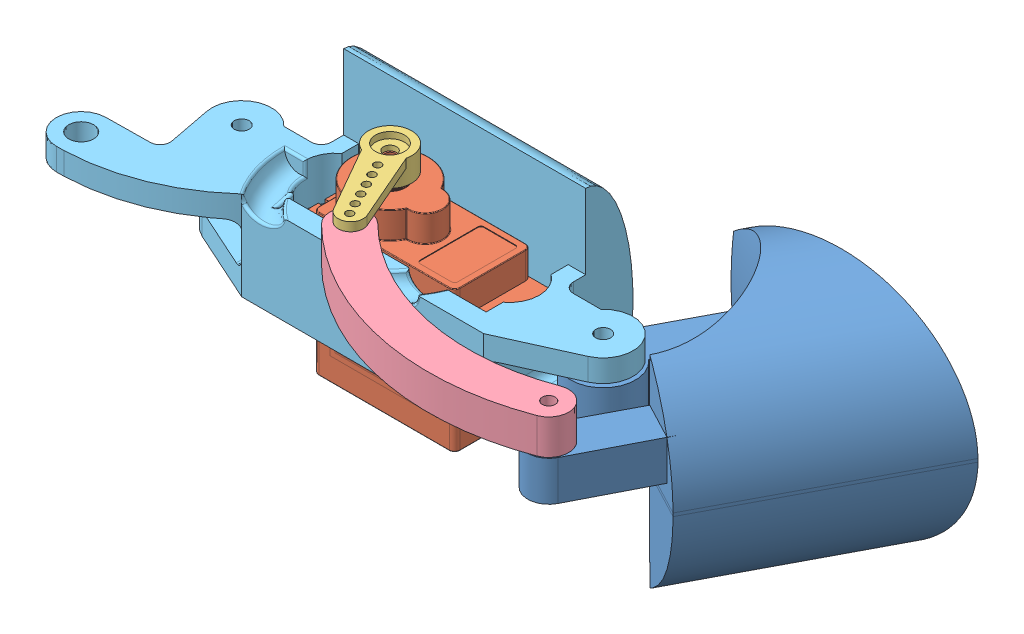
SolidWorks assembly Pouce_Ass, configuration Défaut. Lengths in mm.
Overall size (114.58 59.46 78.01).
6 component instances, 5 part files, 13 mates.
Components (placement in the parent):
- phalange2_Pouce-1: phalange2_Pouce [Défaut] at (-8.353 -22.7384 161.1487) x (0 -1 0) z (-0.466256 0 0.88465) size (59.46 36.8 53.31)
- SG90 - Micro Servo Assembly-1: SG90 - Micro Servo Assembly [Default] at (-39.6946 -27.7064 148.9759) size (32.1 31.75 22.59) (flexible)
  - SG90 - Micro Servo 9g - Tower Pro.1-2: SG90 - Micro Servo 9g - Tower Pro.1 [Peça] at origin size (32.1 29.95 12.4)
  - SG90 - Micro Servo 9g - Tower Pro.2-2: SG90 - Micro Servo 9g - Tower Pro.2 [Peça] at (-5.15 21.1 0) x (-0.448 0 -0.894034) z (0.894034 0 -0.448) size (19.5 3.8 6.9)
- Bras de levier_Pouce-1: Bras de levier_Pouce [Default] at (-11.5118 -8.0064 134.8725) x (0 -1 0) z (-0.704963 0 0.709244) size (5.59 41.05 28.71)
- SG90 - Servo Socket_Pouce-1: SG90 - Servo Socket_Pouce [Default] at (-58.786 -15.7161 158.6946) x (1 0 0) z (0 1 0) size (76.42 33.67 31.75)
Mates (geometry in assembly coordinates):
- Coïncidente1: coincident anti-aligned: plane of SG90 - Micro Servo Assembly-1/SG90 - Micro Servo 9g - Tower Pro.1-2 through (-54.8946 -22.5564 154.2259) normal (0 -1 0); plane of SG90 - Servo Socket-1 through (-62.893 -24.95 145.172) normal (0 1 0)
- Coaxiale1: concentric aligned: cylinder of SG90 - Micro Servo Assembly-1/SG90 - Micro Servo 9g - Tower Pro.1-2 through (-25.7946 -38.2564 148.9759) axis (0 1 0) radius 1.1; cylinder of SG90 - Servo Socket-1 through (-29.9016 -33.7707 135.647) axis (0 1 0) radius 0.508
- Coaxiale4: concentric anti-aligned: circle of SG90 - Servo Socket-1; cylinder of phalange2_Pouce-1 through (-10.653 -52.436 149.1696) axis (0 1 0) radius 1.9812
- Distance3: distance = 0.3969 mm anti-aligned: plane of phalange2_Pouce-1 through (1.6103 -19.5634 114.8431) normal (0 1 0); plane of SG90 - Servo Socket-1 through (-14.76 -21.6658 135.647) normal (0 -1 0)
- Coaxiale5: concentric aligned: cylinder of SG90 - Micro Servo Assembly-1/SG90 - Micro Servo 9g - Tower Pro.2-2 through (-38.371 -6.6064 161.8947) axis (0 1 0) radius 0.6; cylinder of Bras de levier-1 through (-38.371 -13.5944 161.8947) axis (0 1 0) radius 1.1906
- Coïncidente6: coincident anti-aligned: plane of SG90 - Micro Servo Assembly-1/SG90 - Micro Servo 9g - Tower Pro.2-2 through (-44.8446 -8.0064 148.9759) normal (0 -1 0); plane of Bras de levier-1 through (-24.9414 -8.0064 148.3836) normal (0 1 0)
- Coaxiale6: concentric aligned: cylinder of phalange2_Pouce-1 through (1.9977 -52.436 170.497) axis (0 1 0) radius 1.9844; cylinder of Bras de levier-1 through (1.9977 -13.5944 170.497) axis (0 1 0) radius 1.0319
- Parallèle2: parallel anti-aligned: plane of SG90 - Servo Socket-1 through (-55.4159 -32.3338 129.297) normal (0 0 1); plane of SG90 - Micro Servo Assembly-1/SG90 - Micro Servo 9g - Tower Pro.1-2 through (-50.0946 -22.5564 142.8759) normal (0 0 -1)
- Coaxiale12: concentric anti-aligned: circle of SG90 - Micro Servo Assembly-1/SG90 - Micro Servo 9g - Tower Pro.1-2; circle of SG90 - Servo Socket_Pouce-1
- Coïncidente7: coincident anti-aligned: plane of SG90 - Micro Servo Assembly-1/SG90 - Micro Servo 9g - Tower Pro.1-2 through (-54.8946 -22.5564 154.2259) normal (0 -1 0); plane of SG90 - Servo Socket_Pouce-1 through (-58.786 -22.5564 158.6946) normal (0 1 0)
- Coïncidente8: coincident anti-aligned: plane of phalange2_Pouce-1 through (1.9977 -13.5944 170.497) normal (0 1 0); plane of Bras de levier_Pouce-1 through (-24.9414 -13.5944 148.3836) normal (0 -1 0)
- Parallèle6: parallel anti-aligned: plane of SG90 - Micro Servo Assembly-1/SG90 - Micro Servo 9g - Tower Pro.1-2 through (-54.8946 -20.0564 142.8759) normal (0 0 -1); plane of SG90 - Servo Socket_Pouce-1 through (-51.3089 -29.9401 142.4227) normal (0 0 1)
- Coaxiale13: concentric anti-aligned: cylinder of phalange2_Pouce-1 through (-10.653 -52.436 149.1696) axis (0 1 0) radius 1.9812; circle of SG90 - Servo Socket_Pouce-1
